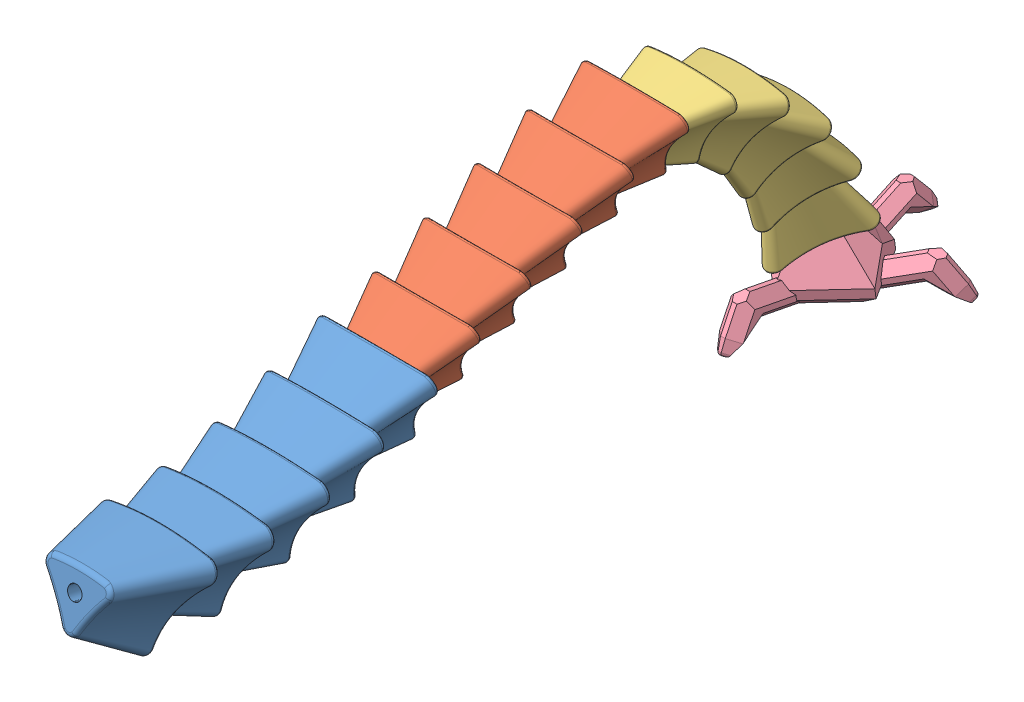
SolidWorks assembly leg, configuration 默认. Lengths in mm.
Overall size (41.94 61.2 185.5).
16 component instances, 4 part files, 3 mates.
Components (placement in the parent):
- leg0-17: leg0 [默认] at (0 -6.6808 -18.9109) x (1 0 0) z (0 0.208527 0.978017) size (26.25 23.37 18.77)
- leg0-32: leg0 [默认] at (0 -6.517 -31.8928) x (1 0 0) z (0 0.06412 0.997942) size (26.25 23.37 18.77)
- leg0-33: leg0 [默认] at (0 -4.0552 -44.7285) x (1 0 0) z (0 -0.100633 0.994924) size (26.25 23.37 18.77)
- leg0-34: leg0 [默认] at (0 0.0222 -57.0382) x (1 0 0) z (0 -0.238379 0.971172) size (26.25 23.37 18.77)
- leg0-35: leg0 [默认] at (0 4.8015 -68.8819) x (1 0 0) z (0 -0.324139 0.946009) size (26.25 23.37 18.77)
- leg1-1: leg1 [默认] at (0 9.1723 -79.1308) x (1 0 0) z (0 -0.363134 0.931737) size (23.62 21.03 16.89)
- leg1-2: leg1 [默认] at (0 13.8017 -89.9818) x (1 0 0) z (0 -0.380186 0.92491) size (23.62 21.03 16.89)
- leg1-3: leg1 [默认] at (0 18.3189 -100.8345) x (1 0 0) z (0 -0.382205 0.924077) size (23.62 21.03 16.89)
- leg1-4: leg1 [默认] at (0 22.6831 -111.7261) x (1 0 0) z (0 -0.375741 0.926725) size (23.62 21.03 16.89)
- leg1-5: leg1 [默认] at (0 25.4629 -122.9469) x (1 0 0) z (0 -0.285433 0.958399) size (23.62 21.03 16.89)
- leg2-1: leg2 [默认] at (0 23.173 -132.8389) x (1 0 0) z (0 -0.006936 0.999976) size (21 18.7 15.02)
- leg2-2: leg2 [默认] at (0 17.3326 -142.2075) x (1 0 0) z (0 0.309174 0.951005) size (21 18.7 15.02)
- leg2-3: leg2 [默认] at (0 9.1728 -149.5513) x (1 0 0) z (0 0.574364 0.8186) size (21 18.7 15.02)
- leg2-4: leg2 [默认] at (0 -0.4711 -154.6709) x (1 0 0) z (0 0.769759 0.638335) size (21 18.7 15.02)
- leg2-5: leg2 [默认] at (0 -10.8629 -157.8197) x (1 0 0) z (0 0.892662 0.450726) size (21 18.7 15.02)
- foot-1: foot [默认] at (0 -23.0232 -160.7914) x (-1 0 0) z (0 0.122108 -0.992517) size (41.94 16.31 46.09)
Mates (geometry in assembly coordinates):
- 重合15: coincident anti-aligned: plane of foot-1 through (0 -23.0232 -160.7914) normal (-1 0 0)
- 重合16: coincident: point of foot-1; curve of assembly
- 重合17: coincident: point of foot-1; curve of assembly
